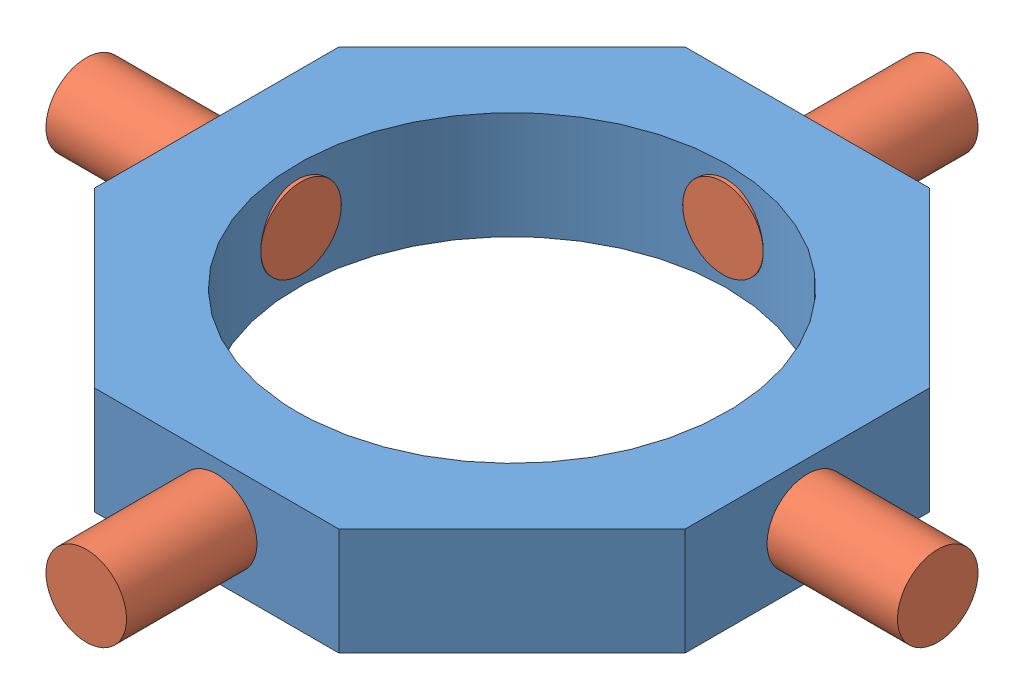
SolidWorks assembly Crosstree Assembly, configuration Default. Lengths in mm.
Overall size (201.4 26.18 201.4).
5 component instances, 2 part files, 3 mates.
Components (placement in the parent):
- Crosstree-1: Crosstree [Default] at (43.0477 61.9283 110.8608) size (139.7 25.4 139.7)
- Crosstree Bearing Rod-1: Crosstree Bearing Rod [Default] at (43.0477 74.6283 10.1618) x (-0.520451 0.853891 0) z (0.853891 0.520451 0) size (19.05 50.8 19.05)
- Crosstree Bearing Rod-2: Crosstree Bearing Rod [Default] at (143.7467 74.6283 110.8608) x (0 0.853891 -0.520451) z (0 0.520451 0.853891) size (19.05 50.8 19.05)
- Crosstree Bearing Rod-3: Crosstree Bearing Rod [Default] at (43.0477 74.6283 211.5599) x (0.520451 0.853891 0) z (-0.853891 0.520451 0) size (19.05 50.8 19.05)
- Crosstree Bearing Rod-4: Crosstree Bearing Rod [Default] at (-57.6514 74.6283 110.8608) x (0 0.853891 0.520451) z (0 0.520451 -0.853891) size (19.05 50.8 19.05)
Mates (geometry in assembly coordinates):
- Tangent1: tangent: curve of Crosstree-1; circle of Crosstree Bearing Rod-1
- Concentric2: concentric anti-aligned: cylinder of Crosstree-1 through (43.0477 74.6283 41.0108) axis (0 0 1) radius 9.525; cylinder of Crosstree Bearing Rod-1 through (43.0477 74.6283 60.9618) axis (0 0 -1) radius 9.525
- Lock1: lock: unknown of Crosstree-1; unknown of Crosstree Bearing Rod-1
